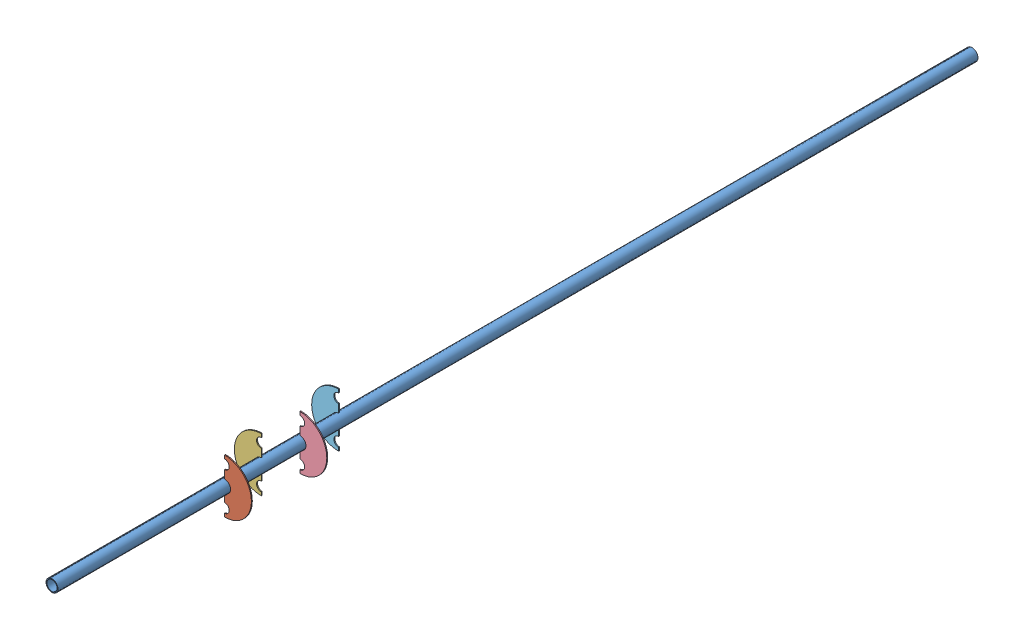
SolidWorks assembly Assem1, configuration Default. Lengths in mm.
Overall size (57 57 976).
5 component instances, 5 part files, 12 mates.
Components (placement in the parent):
- SampleTube_1615-1: SampleTube_1615 [Default] at origin size (12.7 12.7 976)
- Baffle1-3: Baffle1 [Default] at (0 0 793) x (1 0 0) z (0 1 0) size (28.5 1 57)
- Baffle2-2: Baffle2 [Default] at (0 0 753) x (-1 0 0) z (0 1 0) size (28.5 1 57)
- Baffle3-2: Baffle3 [Default] at (0 0 713) x (1 0 0) z (0 1 0) size (28.5 1 57)
- Baffle4-2: Baffle4 [Default] at (0 0 671) x (-1 0 0) z (0 1 0) size (28.5 1 57)
Mates (geometry in assembly coordinates):
- Parallel4: parallel: plane of Baffle1-3 through (0 0 792) normal (0 0 -1); plane of SampleTube_1615-1 through (0 0 976) normal (0 0 1)
- Concentric1: concentric: circle of SampleTube_1615-1; circle of Baffle1-3
- Concentric5: concentric: circle of SampleTube_1615-1; circle of Baffle2-2
- Parallel7: parallel: line of Baffle1-3 through (0 6.45 793) axis (0 1 0); line of Baffle2-2 through (0 6.45 754) axis (0 1 0)
- Distance4: distance = 40 mm: plane of Baffle2-2 through (0 0 753) normal (0 0 -1); plane of Baffle1-3 through (0 0 793) normal (0 0 1)
- Distance5: distance = 183 mm: plane of Baffle1-3 through (0 0 793) normal (0 0 1); plane of SampleTube_1615-1 through (0 0 976) normal (0 0 1)
- Concentric6: concentric: circle of SampleTube_1615-1; circle of Baffle3-2
- Parallel8: parallel: line of Baffle2-2 through (0 6.45 754) axis (0 1 0); line of Baffle3-2 through (0 6.45 713) axis (0 1 0)
- Distance6: distance = 40 mm: plane of Baffle3-2 through (0 0 713) normal (0 0 1); plane of Baffle2-2 through (0 0 753) normal (0 0 -1)
- Concentric7: concentric: circle of SampleTube_1615-1; circle of Baffle4-2
- Distance8: distance = 40 mm: plane of Baffle4-2 through (0 0 672) normal (0 0 1); plane of Baffle3-2 through (0 0 712) normal (0 0 -1)
- Parallel9: parallel aligned: line of Baffle3-2 through (0 6.45 713) axis (0 1 0); line of Baffle4-2 through (0 6.45 672) axis (0 1 0)
